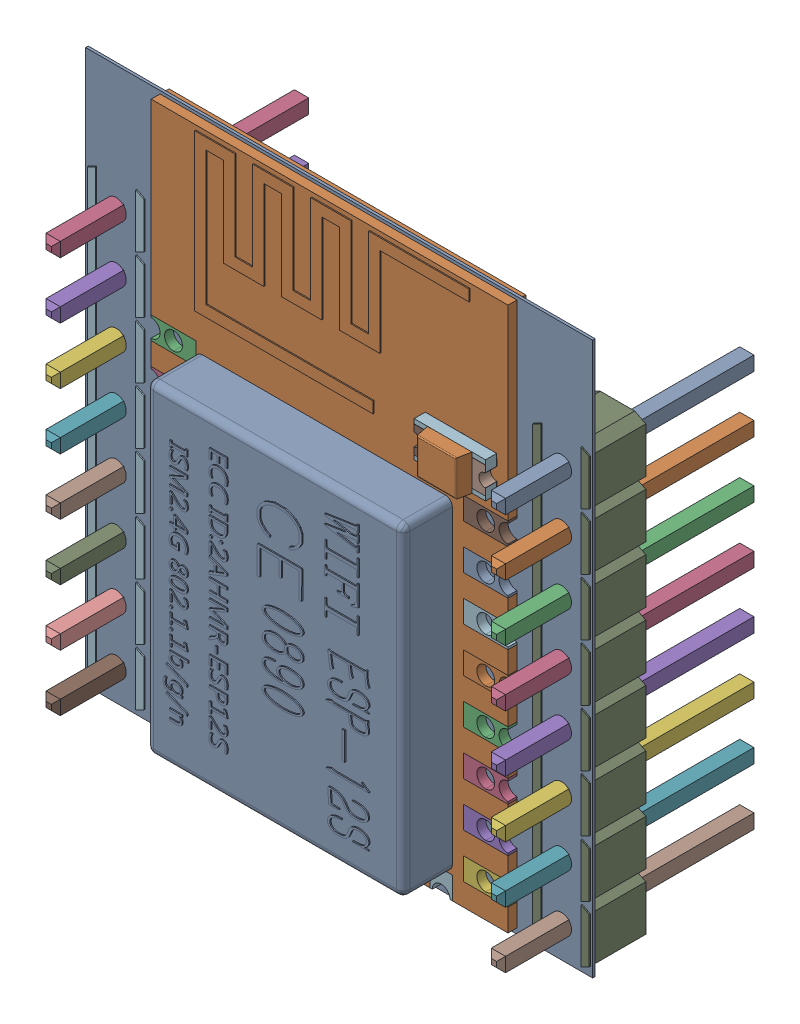
SolidWorks assembly ESP-12S, configuration 默认. Lengths in mm.
Overall size (22.73 24.76 11.54).
51 component instances, 25 part files, 0 mates.
Components (placement in the parent):
- PCB-1-1: PCB-1 [默认] at (0 0 9.144) size (22.73 24.76 11.54)
  - Board-1-1: Board-1 [默认] at origin size (22.73 24.76 0.12)
    - Open CASCADE STEP translator 6.8 1.1.1-1: Open CASCADE STEP translator 6.8 1.1.1 [默认] at (0 0 -0.1168) size (22.73 24.76 0.12)
  - P3-1: P3 [默认] at origin size (16 24.38 3.05)
    - 0411-2-1: 0411-2 [默认] at (11.34 12.4403 0) x (0 1 0) z (-1 0 0) size (24.38 3.05 16)
      - User_Library-ESP8266-12E_PCB1-1: User_Library-ESP8266-12E_PCB1 [默认] x (-1 0 0) z (0 0 1) size (24.38 0.8 16)
      - User_Library-ESP8266-12E_Pin1-1: User_Library-ESP8266-12E_Pin1 [默认] at (3.31 0 8) x (-1 0 0) z (0 -1 0) size (1 2 0.8)
      - User_Library-ESP8266-12E_Pin1-2: User_Library-ESP8266-12E_Pin1 [默认] at (1.31 0 8) x (-1 0 0) z (0 -1 0) size (1 2 0.8)
      - User_Library-ESP8266-12E_Pin1-3: User_Library-ESP8266-12E_Pin1 [默认] at (-0.69 0 8) x (-1 0 0) z (0 -1 0) size (1 2 0.8)
      - User_Library-ESP8266-12E_Pin1-4: User_Library-ESP8266-12E_Pin1 [默认] at (-2.69 0 8) x (-1 0 0) z (0 -1 0) size (1 2 0.8)
      - User_Library-ESP8266-12E_Pin1-5: User_Library-ESP8266-12E_Pin1 [默认] at (-4.69 0 8) x (-1 0 0) z (0 -1 0) size (1 2 0.8)
      - User_Library-ESP8266-12E_Pin1-6: User_Library-ESP8266-12E_Pin1 [默认] at (-6.69 0 8) x (-1 0 0) z (0 -1 0) size (1 2 0.8)
      - User_Library-ESP8266-12E_Pin1-7: User_Library-ESP8266-12E_Pin1 [默认] at (-8.69 0 8) x (-1 0 0) z (0 -1 0) size (1 2 0.8)
      - User_Library-ESP8266-12E_Pin1-8: User_Library-ESP8266-12E_Pin1 [默认] at (-10.69 0 8) x (-1 0 0) z (0 -1 0) size (1 2 0.8)
      - User_Library-ESP8266-12E_Pin1-9: User_Library-ESP8266-12E_Pin1 [默认] at (3.31 0 -8) x (1 0 0) z (0 -1 0) size (1 2 0.8)
      - User_Library-ESP8266-12E_Pin1-10: User_Library-ESP8266-12E_Pin1 [默认] at (-0.69 0 -8) x (1 0 0) z (0 -1 0) size (1 2 0.8)
      - User_Library-ESP8266-12E_Pin1-11: User_Library-ESP8266-12E_Pin1 [默认] at (1.31 0 -8) x (1 0 0) z (0 -1 0) size (1 2 0.8)
      - User_Library-ESP8266-12E_Pin1-12: User_Library-ESP8266-12E_Pin1 [默认] at (-2.69 0 -8) x (1 0 0) z (0 -1 0) size (1 2 0.8)
      - User_Library-ESP8266-12E_Pin1-13: User_Library-ESP8266-12E_Pin1 [默认] at (-4.69 0 -8) x (1 0 0) z (0 -1 0) size (1 2 0.8)
      - User_Library-ESP8266-12E_Pin1-14: User_Library-ESP8266-12E_Pin1 [默认] at (-6.69 0 -8) x (1 0 0) z (0 -1 0) size (1 2 0.8)
      - User_Library-ESP8266-12E_Pin1-15: User_Library-ESP8266-12E_Pin1 [默认] at (-8.69 0 -8) x (1 0 0) z (0 -1 0) size (1 2 0.8)
      - User_Library-ESP8266-12E_Pin1-16: User_Library-ESP8266-12E_Pin1 [默认] at (-10.69 0 -8) x (1 0 0) z (0 -1 0) size (1 2 0.8)
      - User_Library-ESP8266-12E_Pin2-1: User_Library-ESP8266-12E_Pin2 [默认] at (-12.19 0 5) x (0 0 1) z (0 1 0) size (1 1 0.8)
      - User_Library-ESP8266-12E_Pin2-2: User_Library-ESP8266-12E_Pin2 [默认] at (-12.19 0 3) x (0 0 -1) z (0 -1 0) size (1 1 0.8)
      - User_Library-ESP8266-12E_Pin2-3: User_Library-ESP8266-12E_Pin2 [默认] at (-12.19 0 1) x (0 0 1) z (0 1 0) size (1 1 0.8)
      - User_Library-ESP8266-12E_Pin2-4: User_Library-ESP8266-12E_Pin2 [默认] at (-12.19 0 -1) x (0 0 1) z (0 1 0) size (1 1 0.8)
      - User_Library-ESP8266-12E_Pin2-5: User_Library-ESP8266-12E_Pin2 [默认] at (-12.19 0 -3) x (0 0 1) z (0 1 0) size (1 1 0.8)
      - User_Library-ESP8266-12E_Pin2-6: User_Library-ESP8266-12E_Pin2 [默认] at (-12.19 0 -5) x (0 0 1) z (0 1 0) size (1 1 0.8)
      - User_Library-ESP8266-12E_Lid-1: User_Library-ESP8266-12E_Lid [默认] at (-3.84 -1.5 0.25) x (0 0 -1) z (0 -1 0) size (11.5 14.5 2.25)
      - User_Library-ESP8266-12E_Antenne-1: User_Library-ESP8266-12E_Antenne [默认] at (4.99 -0.425 6) x (0 0 -1) z (0 -1 0) size (12.3 7 0.05)
      - User_Library-ESP8266-12E_Surface_Mount_Chip_LED_3.2x1.6mm-1: User_Library-ESP8266-12E_Surface_Mount_Chip_LED_3.2x1.6mm [默认] at (6.19 -0.41 -7.5) x (0 0 1) z (0 -1 0) size (3.2 1.6 1.13)
  - Open CASCADE STEP translator 6.8 1.3-1: Open CASCADE STEP translator 6.8 1.3 [默认] at origin size (2.54 20.32 11.54)
    - Header8_2.54mm-1: Header8_2.54mm [默认] at (1.3969 10.3123 -1.2168) x (0 -1 0) z (1 0 0) size (0.64 11.54 0.64)
    - Header8_2.54mm-2-1: Header8_2.54mm-2 [默认] at (1.3969 10.3123 -1.2168) x (0 -1 0) z (1 0 0) size (0.64 11.54 0.64)
    - Header8_2.54mm-3-1: Header8_2.54mm-3 [默认] at (1.3969 10.3123 -1.2168) x (0 -1 0) z (1 0 0) size (0.64 11.54 0.64)
    - Header8_2.54mm-4-1: Header8_2.54mm-4 [默认] at (1.3969 10.3123 -1.2168) x (0 -1 0) z (1 0 0) size (0.64 11.54 0.64)
    - Header8_2.54mm-5-1: Header8_2.54mm-5 [默认] at (1.3969 10.3123 -1.2168) x (0 -1 0) z (1 0 0) size (0.64 11.54 0.64)
    - Header8_2.54mm-6-1: Header8_2.54mm-6 [默认] at (1.3969 10.3123 -1.2168) x (0 -1 0) z (1 0 0) size (0.64 11.54 0.64)
    - Header8_2.54mm-7-1: Header8_2.54mm-7 [默认] at (1.3969 10.3123 -1.2168) x (0 -1 0) z (1 0 0) size (0.64 11.54 0.64)
    - Header8_2.54mm-8-1: Header8_2.54mm-8 [默认] at (1.3969 10.3123 -1.2168) x (0 -1 0) z (1 0 0) size (0.64 11.54 0.64)
    - Header8_2.54mm-9-1: Header8_2.54mm-9 [默认] at (1.3969 10.3123 -1.2168) x (0 -1 0) z (1 0 0) size (20.32 2.54 2.54)
  - 1-10-1: 1-10 [默认] at origin size (2.54 20.32 11.54)
    - Header8_2.54mm_RGB255-1: Header8_2.54mm_RGB255 [默认] at (21.3613 10.3123 -1.2168) x (0 -1 0) z (1 0 0) size (0.64 11.54 0.64)
    - Header8_2.54mm_RGB255-11-1: Header8_2.54mm_RGB255-11 [默认] at (21.3613 10.3123 -1.2168) x (0 -1 0) z (1 0 0) size (0.64 11.54 0.64)
    - Header8_2.54mm_RGB255-12-1: Header8_2.54mm_RGB255-12 [默认] at (21.3613 10.3123 -1.2168) x (0 -1 0) z (1 0 0) size (0.64 11.54 0.64)
    - Header8_2.54mm_RGB255-13-1: Header8_2.54mm_RGB255-13 [默认] at (21.3613 10.3123 -1.2168) x (0 -1 0) z (1 0 0) size (0.64 11.54 0.64)
    - Header8_2.54mm_RGB255-14-1: Header8_2.54mm_RGB255-14 [默认] at (21.3613 10.3123 -1.2168) x (0 -1 0) z (1 0 0) size (0.64 11.54 0.64)
    - Header8_2.54mm_RGB255-15-1: Header8_2.54mm_RGB255-15 [默认] at (21.3613 10.3123 -1.2168) x (0 -1 0) z (1 0 0) size (0.64 11.54 0.64)
    - Header8_2.54mm_RGB255-16-1: Header8_2.54mm_RGB255-16 [默认] at (21.3613 10.3123 -1.2168) x (0 -1 0) z (1 0 0) size (0.64 11.54 0.64)
    - Header8_2.54mm_RGB255-17-1: Header8_2.54mm_RGB255-17 [默认] at (21.3613 10.3123 -1.2168) x (0 -1 0) z (1 0 0) size (0.64 11.54 0.64)
    - Header8_2.54mm_RGB255-18-1: Header8_2.54mm_RGB255-18 [默认] at (21.3613 10.3123 -1.2168) x (0 -1 0) z (1 0 0) size (20.32 2.54 2.54)
